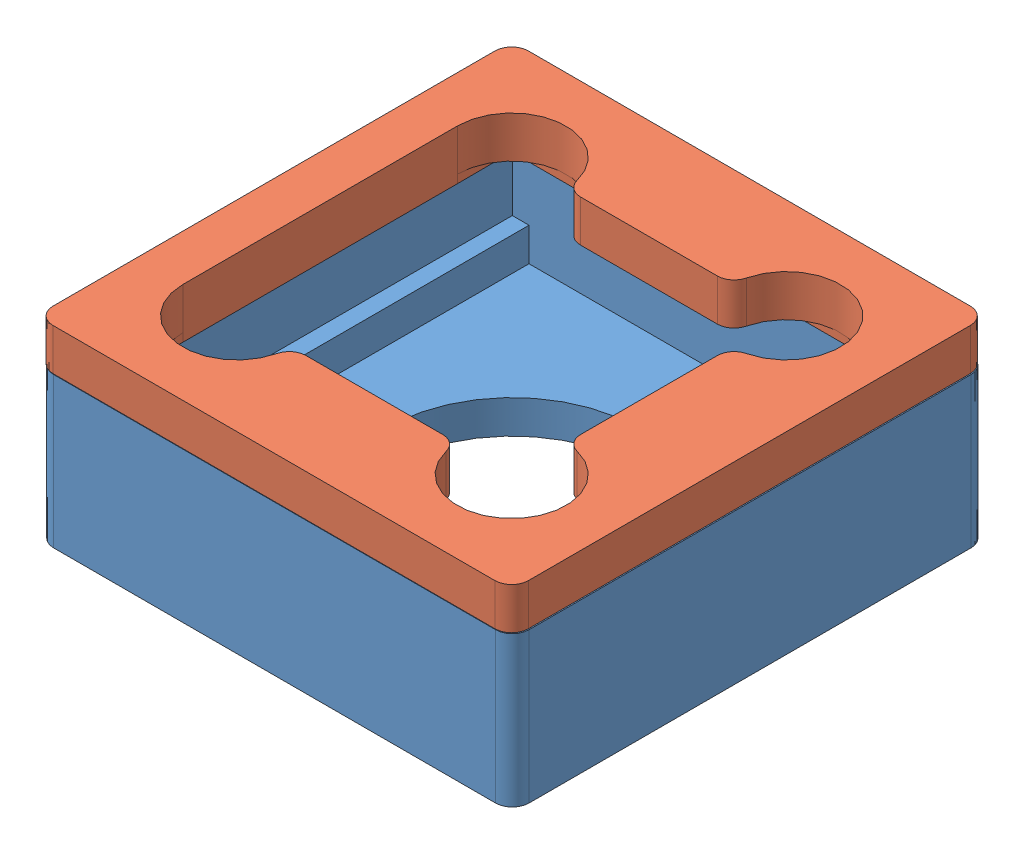
SolidWorks assembly Assembly_oblig1, configuration Default. Lengths in mm.
Overall size (57.04 23.1 57.04).
2 component instances, 2 part files, 1 mates.
Components (placement in the parent):
- box_oblig1-1: box_oblig1 [Default] at origin size (57 18 57)
- lid_oblig1 1-2: lid_oblig1 1 [Default] at (-0.0389 23.1 0.0391) x (-1 0 0) z (0 0 1) size (57 6 57)
Mates (geometry in assembly coordinates):
- Distance2: distance = 0.1 mm anti-aligned: plane of box_oblig1-1 through (0 18 0) normal (0 1 0); plane of lid_oblig1 1-2 through (-0.0389 18.1 0.0391) normal (0 -1 0)
